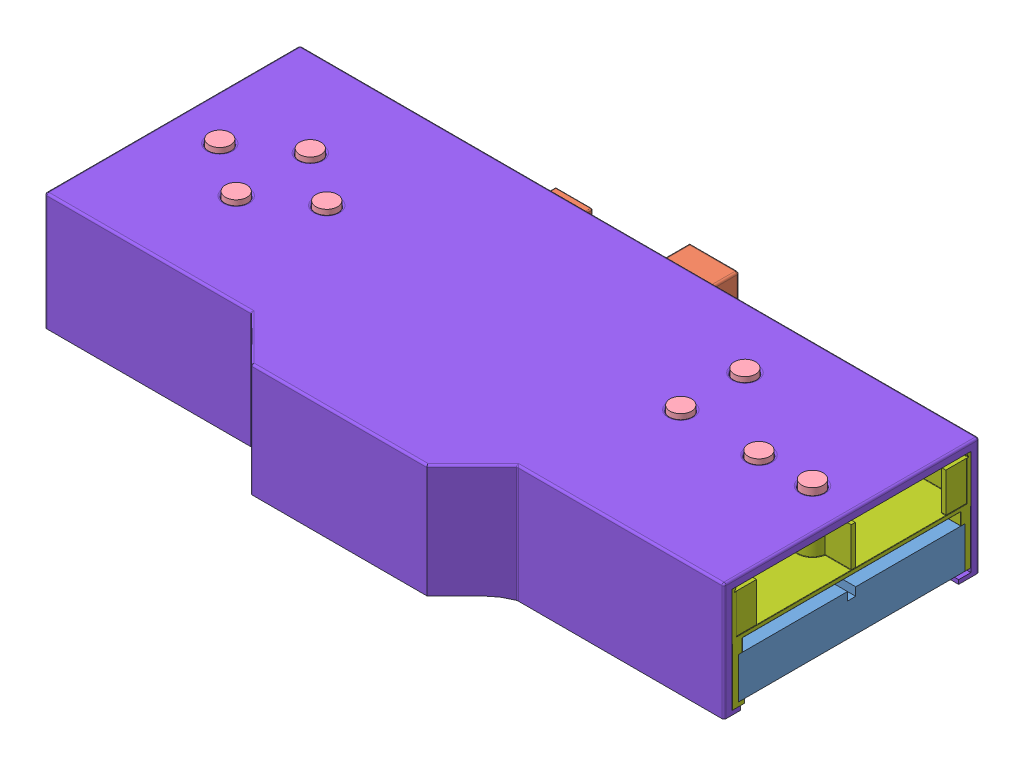
SolidWorks assembly Complete unit 3, configuration Default. Lengths in mm.
Overall size (165 29.95 81.18).
22 component instances, 8 part files, 37 mates.
Components (placement in the parent):
- Breadboard-1: Breadboard [Default] at (74.0469 75.7408 124.2234) size (165 10 56)
- arduino uno-1: arduino uno [Default] at (73.5469 86.7908 125.5463) x (0 0 1) z (-1 0 0) size (76.5 14.6 53)
- Arduino attachment-1: Arduino attachment [Default] at (74.0469 74.7408 128.0463) size (53 14.5 70)
- Button-1: Button [Default] at (146.5469 92.1656 123.7234) x (-0.962765 0 -0.270338) z (0.270338 0 -0.962765) size (5.2 11.5 5.2)
- Button-2: Button [Default] at (133.5469 91.7408 123.7234) x (0.721997 0 0.691896) z (-0.691896 0 0.721997) size (5.2 11.5 5.2)
- Button-3: Button [Default] at (114.5469 91.7408 123.7234) x (0.651784 0 0.758405) z (-0.758405 0 0.651784) size (5.2 11.5 5.2)
- Button-4: Button [Default] at (114.5469 91.7408 108.1385) x (0.607167 0 -0.794574) z (0.794574 0 0.607167) size (5.2 11.5 5.2)
- Button-5: Button [Default] at (15.5469 91.7408 114.7234) x (0.707501 0 -0.706713) z (0.706713 0 0.707501) size (5.2 11.5 5.2)
- Button-6: Button [Default] at (28.5469 91.7408 123.7234) x (0.951274 0 -0.308347) z (0.308347 0 0.951274) size (5.2 11.5 5.2)
- Button-7: Button [Default] at (15.5469 91.7408 132.7234) x (0.996687 0 -0.081336) z (0.081336 0 0.996687) size (5.2 11.5 5.2)
- Button-8: Button [Default] at (2.5469 91.7408 123.7234) x (0.971952 0 -0.235178) z (0.235178 0 0.971952) size (5.2 11.5 5.2)
- Pushbutton-1: Pushbutton [Default] at (2.5469 85.7408 123.7234) size (6 5 6)
- Pushbutton-2: Pushbutton [Default] at (15.5469 85.7408 114.7234) size (6 5 6)
- Pushbutton-3: Pushbutton [Default] at (15.5469 85.7408 132.7234) size (6 5 6)
- Pushbutton-4: Pushbutton [Default] at (28.5469 85.7408 123.7234) size (6 5 6)
- Pushbutton-5: Pushbutton [Default] at (114.5469 85.7408 108.1385) size (6 5 6)
- Pushbutton-6: Pushbutton [Default] at (114.5469 85.7408 123.7234) size (6 5 6)
- Pushbutton-7: Pushbutton [Default] at (133.5469 85.7408 123.7234) size (6 5 6)
- Pushbutton-8: Pushbutton [Default] at (146.5469 85.7408 123.7234) size (6 5 6)
- Dpad1 V2-1: Dpad1 V2 [Default] at (18.0469 88.7408 124.2234) x (0 0 1) z (-1 0 0) size (58 25.5 53)
- Dpad2 V2-1: Dpad2 V2 [Default] at (130.0469 88.7408 124.2234) x (0 0 1) z (-1 0 0) size (58 25.5 53)
- Controller cover-1: Controller cover [Default] at (74.0469 102.2408 124.2234) size (165 28.53 73)
Mates (geometry in assembly coordinates):
- Coincident9: coincident anti-aligned: plane of Breadboard-1 through (74.0469 85.7408 124.2234) normal (0 1 0); plane of arduino uno-1 through (97.5469 85.7408 156.0463) normal (0 -1 0)
- Concentric1: concentric aligned: cylinder of arduino uno-1 through (55.0469 88.7908 159.0463) axis (0 -1 0) radius 2; cylinder of Arduino attachment-1 through (55.0469 86.7408 159.0463) axis (0 -1 0) radius 2
- Coincident11: coincident anti-aligned: plane of Breadboard-1 through (74.0469 75.7408 124.2234) normal (0 -1 0); plane of Arduino attachment-1 through (74.0469 75.7408 128.0463) normal (0 1 0)
- Coincident27: coincident anti-aligned: plane of Breadboard-1 through (74.0469 85.7408 124.2234) normal (0 1 0); plane of Pushbutton-1 through (2.5469 85.7408 123.7234) normal (0 -1 0)
- Coincident28: coincident anti-aligned: plane of Breadboard-1 through (74.0469 85.7408 124.2234) normal (0 1 0); plane of Pushbutton-2 through (15.5469 85.7408 114.7234) normal (0 -1 0)
- Coincident29: coincident anti-aligned: plane of Breadboard-1 through (74.0469 85.7408 124.2234) normal (0 1 0); plane of Pushbutton-4 through (28.5469 85.7408 123.7234) normal (0 -1 0)
- Coincident30: coincident anti-aligned: plane of Breadboard-1 through (74.0469 85.7408 124.2234) normal (0 1 0); plane of Pushbutton-3 through (15.5469 85.7408 132.7234) normal (0 -1 0)
- Coincident31: coincident anti-aligned: plane of Breadboard-1 through (74.0469 85.7408 124.2234) normal (0 1 0); plane of Pushbutton-5 through (114.5469 85.7408 108.1385) normal (0 -1 0)
- Coincident32: coincident anti-aligned: plane of Breadboard-1 through (74.0469 85.7408 124.2234) normal (0 1 0); plane of Pushbutton-6 through (114.5469 85.7408 123.7234) normal (0 -1 0)
- Coincident33: coincident anti-aligned: plane of Breadboard-1 through (74.0469 85.7408 124.2234) normal (0 1 0); plane of Pushbutton-8 through (146.5469 85.7408 123.7234) normal (0 -1 0)
- Coincident34: coincident anti-aligned: plane of Breadboard-1 through (74.0469 85.7408 124.2234) normal (0 1 0); plane of Pushbutton-7 through (133.5469 85.7408 123.7234) normal (0 -1 0)
- Coincident35: coincident anti-aligned: plane of Breadboard-1 through (-8.4531 85.7408 96.7234) normal (0 0 -1); plane of Dpad2 V2-1 through (156.5469 75.7408 96.7234) normal (0 0 1)
- Coincident36: coincident aligned: plane of Breadboard-1 through (156.5469 85.7408 151.7234) normal (1 0 0); plane of Dpad2 V2-1 through (156.5469 89.7408 96.7234) normal (1 0 0)
- Coincident39: coincident aligned: plane of Breadboard-1 through (74.0469 75.7408 124.2234) normal (0 -1 0); plane of Dpad2 V2-1 through (130.0469 75.7408 124.2234) normal (0 -1 0)
- Coincident40: coincident anti-aligned: plane of Breadboard-1 through (-8.4531 85.7408 96.7234) normal (0 0 -1); plane of Dpad1 V2-1 through (44.5469 75.7408 96.7234) normal (0 0 1)
- Coincident41: coincident aligned: plane of Breadboard-1 through (-8.4531 85.7408 151.7234) normal (-1 0 0); plane of Dpad1 V2-1 through (-8.4531 89.7408 96.7234) normal (-1 0 0)
- Coincident42: coincident aligned: plane of Breadboard-1 through (74.0469 75.7408 124.2234) normal (0 -1 0); plane of Dpad1 V2-1 through (18.0469 75.7408 124.2234) normal (0 -1 0)
- Concentric2: concentric anti-aligned: cylinder of Button-6 through (28.5469 103.2408 123.7234) axis (0 -1 0) radius 2.6; cylinder of Dpad1 V2-1 through (28.5469 88.7408 123.7234) axis (0 1 0) radius 2.55
- Concentric3: concentric anti-aligned: cylinder of Button-7 through (15.5469 103.2408 132.7234) axis (0 -1 0) radius 2.6; cylinder of Dpad1 V2-1 through (15.5469 88.7408 132.7234) axis (0 1 0) radius 2.55
- Concentric4: concentric anti-aligned: cylinder of Button-8 through (2.5469 103.2408 123.7234) axis (0 -1 0) radius 2.6; cylinder of Dpad1 V2-1 through (2.5469 88.7408 123.7234) axis (0 1 0) radius 2.55
- Concentric5: concentric anti-aligned: cylinder of Button-5 through (15.5469 103.2408 114.7234) axis (0 -1 0) radius 2.6; cylinder of Dpad1 V2-1 through (15.5469 88.7408 114.7234) axis (0 1 0) radius 2.55
- Concentric6: concentric anti-aligned: cylinder of Button-4 through (114.5469 103.2408 108.1385) axis (0 -1 0) radius 2.6; cylinder of Dpad2 V2-1 through (114.5469 88.7408 108.1385) axis (0 1 0) radius 2.6
- Concentric7: concentric anti-aligned: cylinder of Button-3 through (114.5469 103.2408 123.7234) axis (0 -1 0) radius 2.6; cylinder of Dpad2 V2-1 through (114.5469 88.7408 123.7234) axis (0 1 0) radius 2.6
- Concentric8: concentric anti-aligned: cylinder of Button-2 through (133.5469 103.2408 123.7234) axis (0 -1 0) radius 2.6; cylinder of Dpad2 V2-1 through (133.5469 88.7408 123.7234) axis (0 1 0) radius 2.6
- Concentric9: concentric anti-aligned: cylinder of Button-1 through (146.5469 103.6656 123.7234) axis (0 -1 0) radius 2.6; cylinder of Dpad2 V2-1 through (146.5469 88.7408 123.7234) axis (0 1 0) radius 2.6
- Coincident43: coincident anti-aligned: plane of Dpad1 V2-1 through (44.5469 75.7408 153.2234) normal (0 0 1); plane of Controller cover-1 through (-8.4531 74.7408 153.2234) normal (0 0 -1)
- Coincident44: coincident aligned: plane of Dpad1 V2-1 through (-8.4531 89.7408 96.7234) normal (-1 0 0); plane of Controller cover-1 through (-8.4531 74.7408 155.2234) normal (-1 0 0)
- Coincident45: coincident aligned: plane of Dpad1 V2-1 through (18.0469 74.7408 124.2234) normal (0 -1 0); plane of Controller cover-1 through (74.0469 74.7408 124.2234) normal (0 -1 0)
- Distance1: distance = 1.4248 mm aligned: plane of Button-1 through (146.5469 103.6656 123.7234) normal (0 1 0); plane of Controller cover-1 through (74.0469 102.2408 124.2234) normal (0 1 0)
- Distance2: distance = 1 mm aligned: plane of Button-2 through (133.5469 103.2408 123.7234) normal (0 1 0); plane of Controller cover-1 through (74.0469 102.2408 124.2234) normal (0 1 0)
- Distance3: distance = 1 mm aligned: plane of Button-3 through (114.5469 103.2408 123.7234) normal (0 1 0); plane of Controller cover-1 through (74.0469 102.2408 124.2234) normal (0 1 0)
- Distance4: distance = 1 mm aligned: plane of Button-4 through (114.5469 103.2408 108.1385) normal (0 1 0); plane of Controller cover-1 through (74.0469 102.2408 124.2234) normal (0 1 0)
- Distance5: distance = 1 mm aligned: plane of Button-6 through (28.5469 103.2408 123.7234) normal (0 1 0); plane of Controller cover-1 through (74.0469 102.2408 124.2234) normal (0 1 0)
- Distance6: distance = 1 mm aligned: plane of Controller cover-1 through (74.0469 102.2408 124.2234) normal (0 1 0); plane of Button-5 through (15.5469 103.2408 114.7234) normal (0 1 0)
- Distance7: distance = 1 mm aligned: plane of Button-8 through (2.5469 103.2408 123.7234) normal (0 1 0); plane of Controller cover-1 through (74.0469 102.2408 124.2234) normal (0 1 0)
- Distance8: distance = 1 mm aligned: plane of Button-7 through (15.5469 103.2408 132.7234) normal (0 1 0); plane of Controller cover-1 through (74.0469 102.2408 124.2234) normal (0 1 0)
- Distance9: distance = 3 mm anti-aligned: plane of Controller cover-1 through (44.5469 74.7408 84.2234) normal (1 0 0); plane of Arduino attachment-1 through (47.5469 75.7408 163.0463) normal (-1 0 0)
